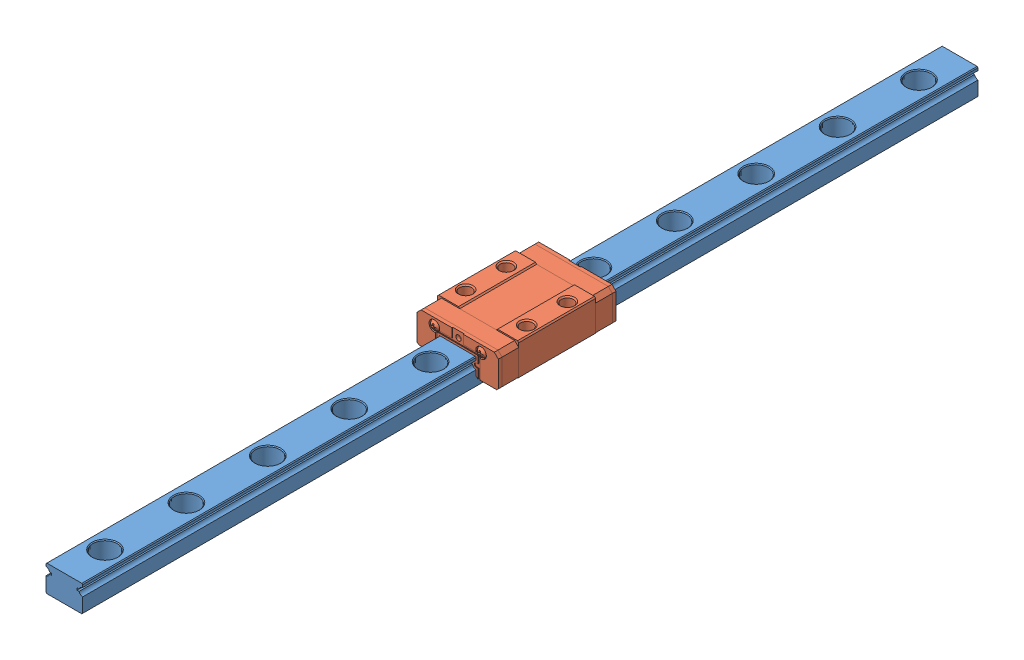
SolidWorks assembly MGN9-250, configuration По умолчанию. Lengths in mm.
Overall size (20 10 220).
2 component instances, 2 part files, 3 mates.
Components (placement in the parent):
- MGNR9-1: MGNR9 [По умолчанию] at origin size (9 6.5 220)
- MGN9C-1: MGN9C [По умолчанию] at (0 2.75 108.8941) size (20 8 29.67)
Mates (geometry in assembly coordinates):
- 重合/共線/共點1: coordinate: point of MGNR9-1
- 同軸心1: concentric anti-aligned: cylinder of MGNR9-1 through (-4.6 1.45 220) axis (0 0 -1) radius 1; cylinder of MGN9C-1 through (-4.6 1.45 94.4441) axis (0 0 1) radius 1
- 同軸心2: concentric anti-aligned: cylinder of MGNR9-1 through (4.6 1.45 220) axis (0 0 -1) radius 1; cylinder of MGN9C-1 through (4.6 1.45 94.4441) axis (0 0 1) radius 1
